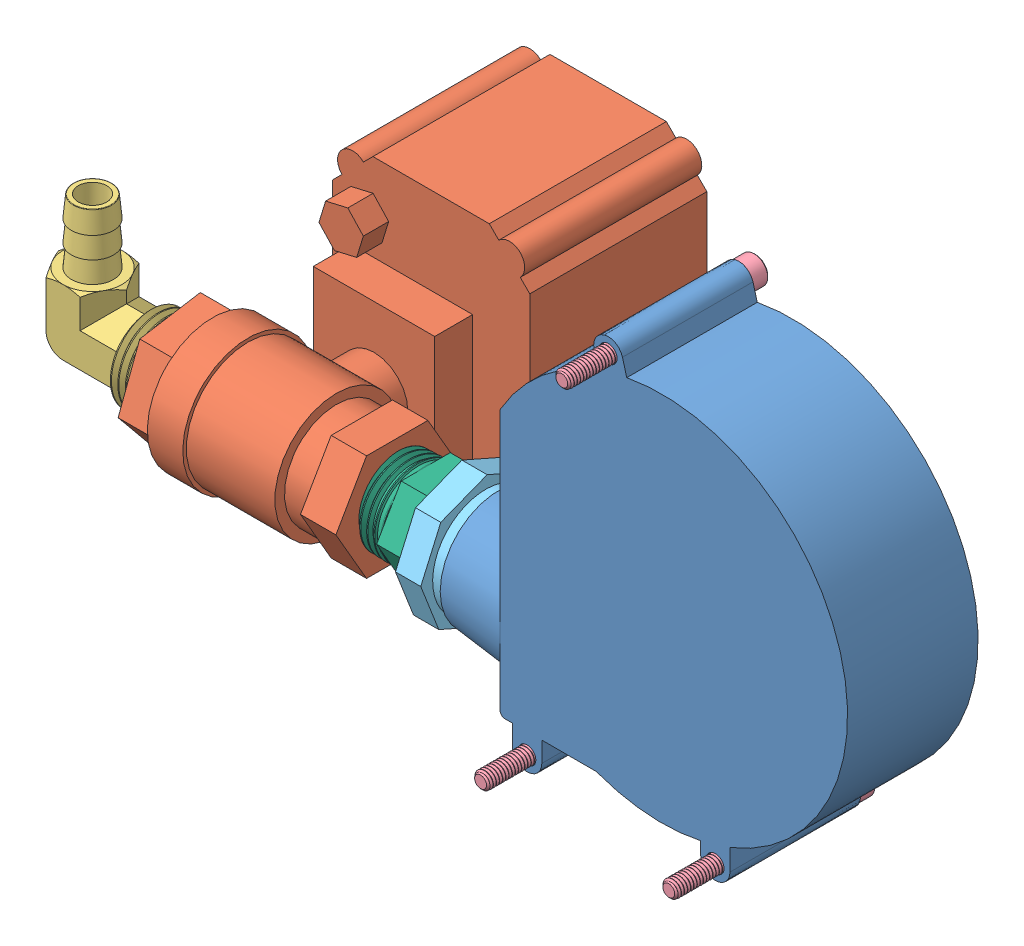
SolidWorks assembly Air Flush In, configuration Default. Lengths in mm.
Overall size (214.49 137.69 134.81).
8 component instances, 6 part files, 17 mates.
Components (placement in the parent):
- blower_fan-1: blower_fan [Default] at (-56.4016 -6.3131 30.4609) size (104.04 104.82 32.77)
- ball_valve-1: ball_valve [Default] at (-230.4766 -21.6439 55.6377) x (0 -0.741838 0.670579) z (0 0.670579 0.741838) size (97.09 58.17 86.85)
- 050NPT to  375ID 90 degBRASS BARBED HOSE FITTING-1: 050NPT to  375ID 90 degBRASS BARBED HOSE FITTING [53525K57] at (-251.9801 -18.6522 46.8439) x (0 0 1) z (0 1 0) size (21.38 36.49 38.89)
- 8-32_screw 1.75-1: 8-32_screw 1.75 [92196A204] at (-106.1108 55.9466 74.9109) size (6.86 6.86 49.17)
- 8-32_screw 1.75-2: 8-32_screw 1.75 [92196A204] at (-79.2524 -41.5122 74.9109) x (0.987351 0.158553 0) z (0 0 1) size (6.86 6.86 49.17)
- 8-32_screw 1.75-4: 8-32_screw 1.75 [92196A204] at (-126.4964 -41.5122 74.9109) x (0.949722 0.313094 0) z (0 0 1) size (6.86 6.86 49.17)
- PVC pipe bushing 3_4 male to 1_2 femal-1: PVC pipe bushing 3_4 male to 1_2 femal [4880K313] at (-127.0669 -18.6522 46.8439) x (1 0 0) z (0 0.02158 0.999767) size (32.54 32.65 32.65)
- 1_2 NPT pvc pipe adapter-1: 1_2 NPT pvc pipe adapter [4880K651] at (-168.3419 -18.6522 46.8439) x (-1 0 0) z (0 -0.866025 -0.5) size (43.34 22.32 24.64)
Mates (geometry in assembly coordinates):
- Parallel1: parallel aligned: plane of blower_fan-1 through (-122.8134 -36.4322 63.2269) normal (0 -1 0); plane of ball_valve-1 through (-172.3106 -41.2582 -27.7051) normal (0 -1 0)
- Concentric3: concentric anti-aligned: cylinder of ball_valve-1 through (-230.4766 -18.6522 46.8439) axis (1 0 0) radius 9.144; cylinder of 050NPT to  375ID 90 degBRASS BARBED HOSE FITTING-1 through (-251.9801 -18.6522 46.8439) axis (-1 0 0) radius 5.207
- Parallel2: parallel aligned: plane of 050NPT to  375ID 90 degBRASS BARBED HOSE FITTING-1 through (-247.7054 -18.6522 54.248) normal (0 0 1); plane of blower_fan-1 through (-92.6816 7.2172 63.2269) normal (0 0 1)
- Distance1: distance = 12.954 mm: plane of ball_valve-1 through (-230.4766 -21.6439 55.6377) normal (-1 0 0); line of 050NPT to  375ID 90 degBRASS BARBED HOSE FITTING-1 through (-243.4306 -10.1027 46.8439) axis (0 1 0)
- Concentric4: concentric anti-aligned: cylinder of blower_fan-1 through (-106.1108 55.9466 63.2269) axis (0 0 -1) radius 2.1971; cylinder of 8-32_screw 1.75-1 through (-106.1108 55.9466 30.4609) axis (0 0 1) radius 2.0828
- Coincident3: coincident anti-aligned: plane of blower_fan-1 through (-92.6816 7.2172 30.4609) normal (0 0 -1); plane of 8-32_screw 1.75-1 through (-106.1108 55.9466 30.4609) normal (0 0 1)
- Concentric5: concentric anti-aligned: cylinder of blower_fan-1 through (-79.2524 -41.5122 63.2269) axis (0 0 -1) radius 2.1971; cylinder of 8-32_screw 1.75-2 through (-79.2524 -41.5122 30.4609) axis (0 0 1) radius 2.0828
- Coincident4: coincident anti-aligned: plane of blower_fan-1 through (-92.6816 7.2172 30.4609) normal (0 0 -1); plane of 8-32_screw 1.75-2 through (-79.2524 -41.5122 30.4609) normal (0 0 1)
- Concentric6: concentric anti-aligned: cylinder of blower_fan-1 through (-126.4964 -41.5122 63.2269) axis (0 0 -1) radius 2.1971; cylinder of 8-32_screw 1.75-4 through (-126.4964 -41.5122 30.4609) axis (0 0 1) radius 2.0828
- Coincident6: coincident anti-aligned: plane of blower_fan-1 through (-92.6816 7.2172 30.4609) normal (0 0 -1); plane of 8-32_screw 1.75-4 through (-126.4964 -41.5122 30.4609) normal (0 0 1)
- Concentric7: concentric anti-aligned: cone of PVC pipe bushing 3_4 male to 1_2 femal-1 through (-137.3856 -18.6522 46.8439) axis (1 0 0); cylinder of 1_2 NPT pvc pipe adapter-1 through (-188.192 -18.6522 46.8439) axis (-1 0 0) radius 10.668
- Concentric8: concentric aligned: cylinder of blower_fan-1 through (-46.0421 -18.6522 46.8439) axis (-1 0 0) radius 12.7; cylinder of PVC pipe bushing 3_4 male to 1_2 femal-1 through (-159.6106 -18.6522 46.8439) axis (-1 0 0) radius 13.335
- Distance2: distance = 3.175 mm anti-aligned: plane of PVC pipe bushing 3_4 male to 1_2 femal-1 through (-153.2606 -10.0669 66.3678) normal (1 0 0); plane of blower_fan-1 through (-150.0856 -18.6522 46.8439) normal (-1 0 0)
- Coincident9: coincident anti-aligned: plane of PVC pipe bushing 3_4 male to 1_2 femal-1 through (-159.6106 -31.9841 47.1317) normal (-1 0 0); plane of 1_2 NPT pvc pipe adapter-1 through (-159.6106 -12.1895 57.3309) normal (1 0 0)
- Distance4: distance = 7.1437 mm anti-aligned: plane of 1_2 NPT pvc pipe adapter-1 through (-168.3419 -7.9842 53.0031) normal (-1 0 0); plane of ball_valve-1 through (-175.4856 -21.6439 55.6377) normal (1 0 0)
- Concentric9: concentric anti-aligned: cylinder of ball_valve-1 through (-230.4766 -18.6522 46.8439) axis (1 0 0) radius 9.144; cylinder of 1_2 NPT pvc pipe adapter-1 through (-188.192 -18.6522 46.8439) axis (-1 0 0) radius 7.8994
- Parallel3: parallel aligned: plane of 1_2 NPT pvc pipe adapter-1 through (-159.6106 -7.9842 53.0031) normal (0 1 0); plane of ball_valve-1 through (-172.3106 22.7498 -27.7051) normal (0 1 0)
